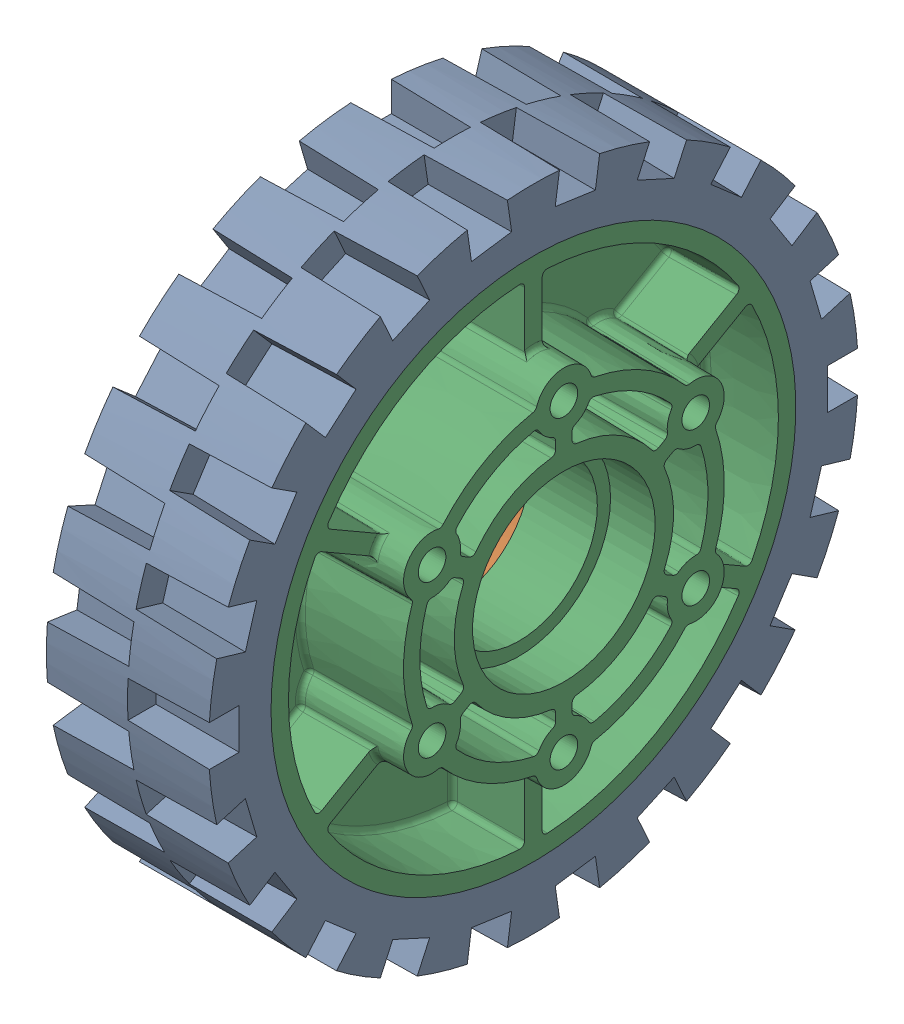
SolidWorks assembly 4 in HiGrip Wheel, configuration Default. Lengths in mm.
Overall size (35.12 101.6 101.6).
2 component instances, 2 part files, 0 mates.
Components (placement in the parent):
- 4 in tread-1: 4 in tread [Default] at (-8.0517 2.5236 2.5343) size (25.4 101.6 101.6)
- 4in 2013 Hub-1: 4in 2013 Hub [Default] at (-8.0517 2.5236 2.5343) size (35.12 82.55 82.55)
